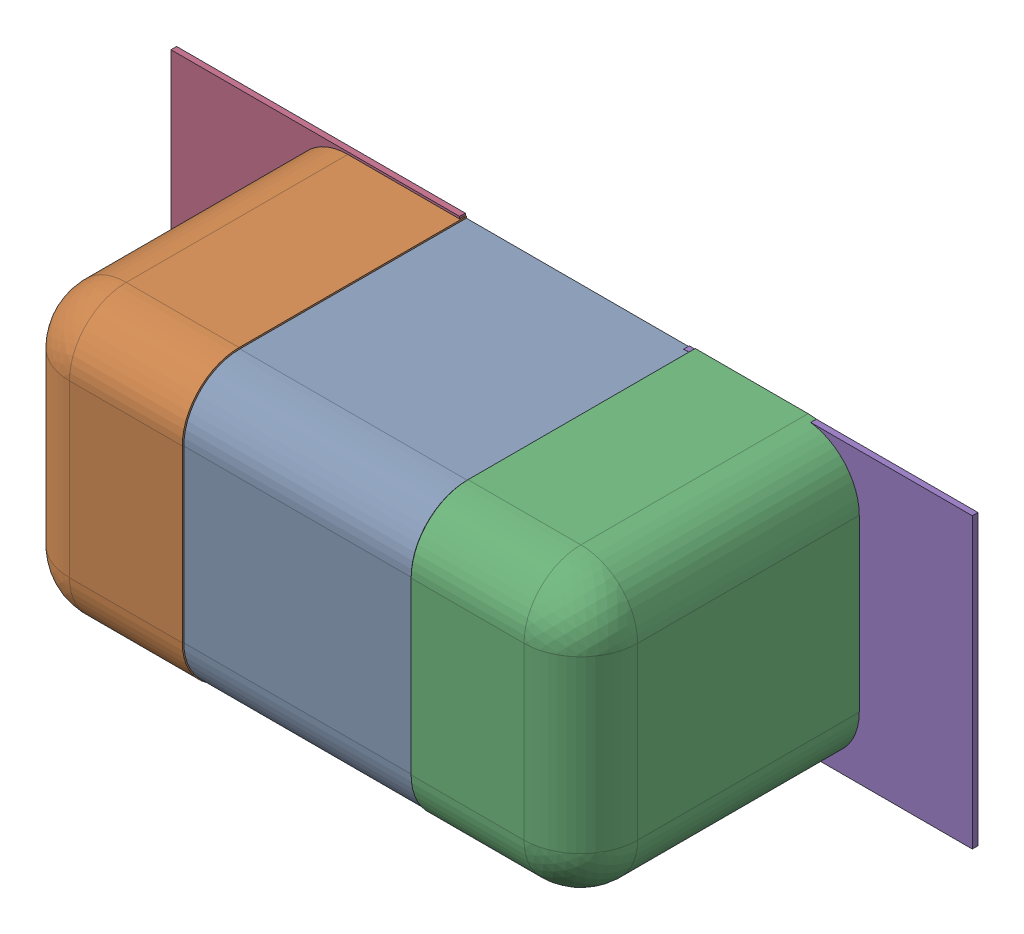
SolidWorks assembly C140, configuration Défaut. Lengths in mm.
Overall size (1.41 0.51 0.5).
8 component instances, 4 part files, 0 mates.
Components (placement in the parent):
- 6324936752-1: 6324936752 [Défaut] at (12.1722 -24.566 0) x (1 0 0) z (0 -1 0) size (1 0.5 0.5)
  - Open CASCADE STEP translator 7.5 2.114.1.1-1: Open CASCADE STEP translator 7.5 2.114.1.1 [Défaut] at origin size (0.4 0.5 0.5)
  - Open CASCADE STEP translator 7.5 2.114.1.2-1: Open CASCADE STEP translator 7.5 2.114.1.2 [Défaut] at origin size (0.3 0.5 0.5)
  - Open CASCADE STEP translator 7.5 2.114.1.3-1: Open CASCADE STEP translator 7.5 2.114.1.3 [Défaut] at origin size (0.3 0.5 0.5)
- 6504207776-1: 6504207776 [Défaut] at (11.7149 -24.5661 0) size (0.51 0.51 0.01)
  - Extruded-1: Extruded [Défaut] at origin size (0.51 0.51 0.01)
- 6504207776-2: 6504207776 [Défaut] at (12.6172 -24.5712 0) size (0.51 0.51 0.01)
  - Extruded-1: Extruded [Défaut] at origin size (0.51 0.51 0.01)
